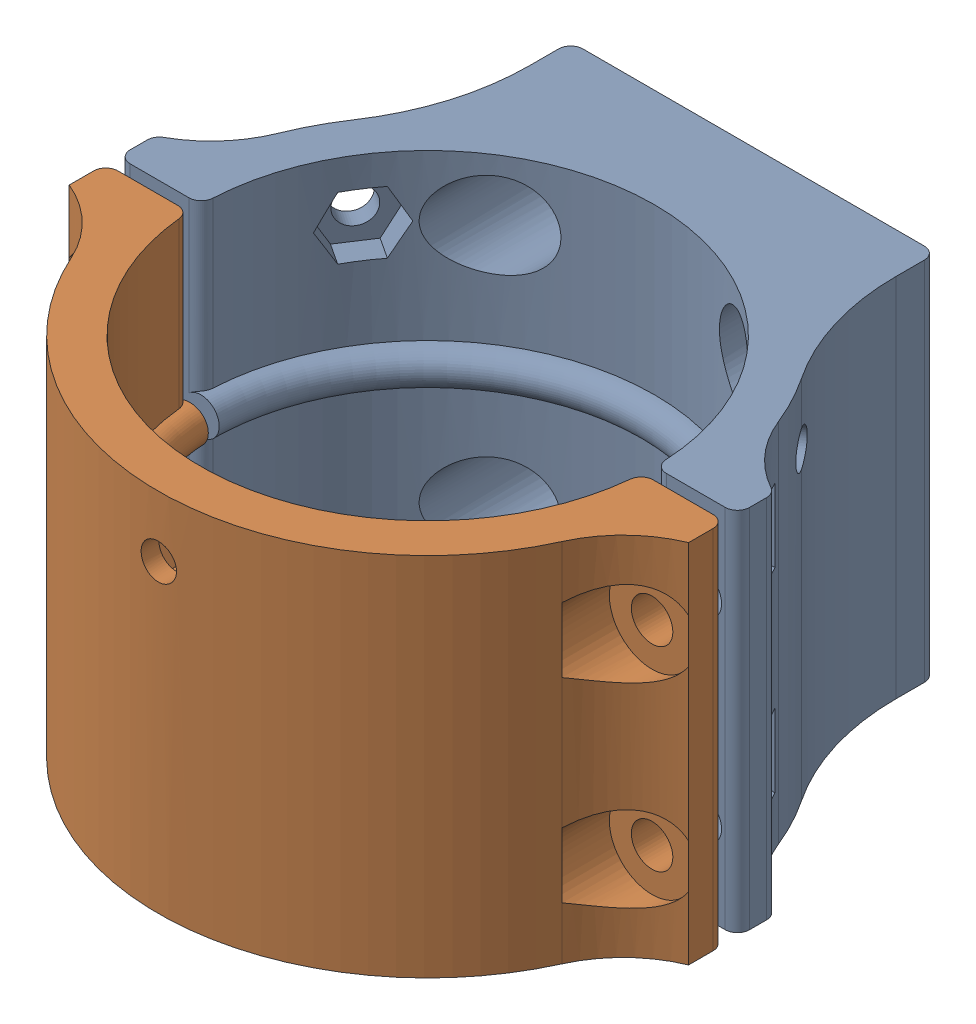
SolidWorks assembly asm_support_reglable_v2, configuration Défaut. Lengths in mm.
Overall size (51.8 30 48.83).
2 component instances, 2 part files, 5 mates.
Components (placement in the parent):
- support_2parties_partFixed_v2-1: support_2parties_partFixed_v2 [Défaut] at origin size (50.8 30 26.73)
- support_2parties_partAdd_v2-1: support_2parties_partAdd_v2 [Défaut] at (0 0 48.8299) x (-1 0 0) z (0 0 -1) size (51.8 30 21.18)
Mates (geometry in assembly coordinates):
- Coïncidente11: coincident aligned: line of support_2parties_partFixed_v2-1 through (0 15 26.7299) axis (0 -1 0); line of support_2parties_partAdd_v2-1 through (0 15 26.7299) axis (0 -1 0)
- Coaxiale6: concentric anti-aligned: cylinder of support_2parties_partFixed_v2-1 through (-22.4 8 26.7299) axis (0 0 1) radius 1.7; cylinder of support_2parties_partAdd_v2-1 through (-22.4 8 27.7299) axis (0 0 -1) radius 1.7
- Coaxiale7: concentric anti-aligned: cylinder of support_2parties_partAdd_v2-1 through (22.4 -8 27.7299) axis (0 0 -1) radius 1.7; cylinder of support_2parties_partFixed_v2-1 through (22.4 -8 26.7299) axis (0 0 1) radius 1.7
- Coaxiale8: concentric anti-aligned: cylinder of support_2parties_partFixed_v2-1 through (-22.4 -8 26.7299) axis (0 0 1) radius 1.7; cylinder of support_2parties_partAdd_v2-1 through (-22.4 -8 27.7299) axis (0 0 -1) radius 1.7
- Coaxiale9: concentric anti-aligned: cylinder of support_2parties_partFixed_v2-1 through (22.4 8 26.7299) axis (0 0 1) radius 1.7; cylinder of support_2parties_partAdd_v2-1 through (22.4 8 27.7299) axis (0 0 -1) radius 1.7
